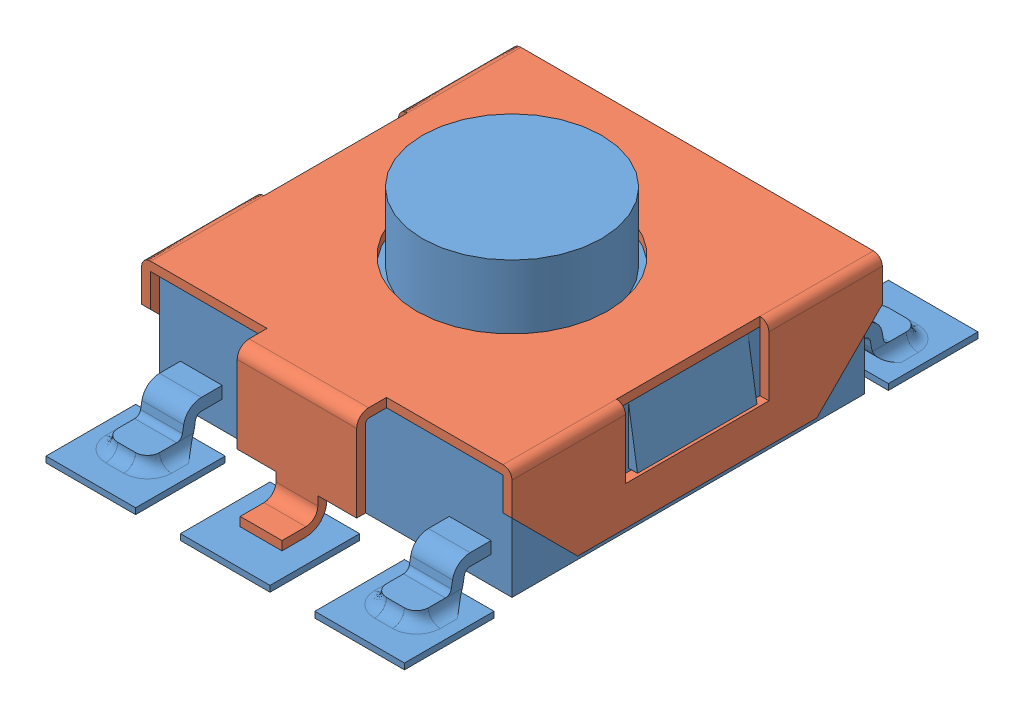
SolidWorks assembly RESET BUTTON, configuration Default. Lengths in mm.
Overall size (6.2 3.1 9.6).
2 component instances, 2 part files, 6 mates.
Components (placement in the parent):
- RESET CORE-1: RESET CORE [Default] at (0 0.1 0) x (-1 0 0) z (0 0 -1) size (6.2 3.1 9.6)
- RESET-1: RESET [Default] at (0 0.1 0) x (0 0 1) z (-1 0 0) size (7.3 2 6.2)
Mates (geometry in assembly coordinates):
- Coincident4: coincident anti-aligned: plane of RESET CORE-1 through (0 0.1 0) normal (0 0 -1)
- Coincident5: coincident anti-aligned: plane of RESET CORE-1 through (0 0.1 0) normal (-1 0 0); plane of assembly through (0 0 0) normal (1 0 0)
- Coincident6: coincident anti-aligned: plane of RESET CORE-1 through (0 0 0) normal (0 -1 0); plane of assembly through (0 0 0) normal (0 1 0)
- Coincident7: coincident aligned: plane of RESET-1 through (0 0.1 0) normal (0 0 1)
- Coincident9: coincident anti-aligned: plane of RESET-1 through (0 0.1 0) normal (-1 0 0); plane of assembly through (0 0 0) normal (1 0 0)
- Coincident10: coincident aligned: plane of RESET CORE-1 through (0 0.1 0) normal (0 1 0); plane of RESET-1 through (0 0.1 0) normal (0 1 0)
